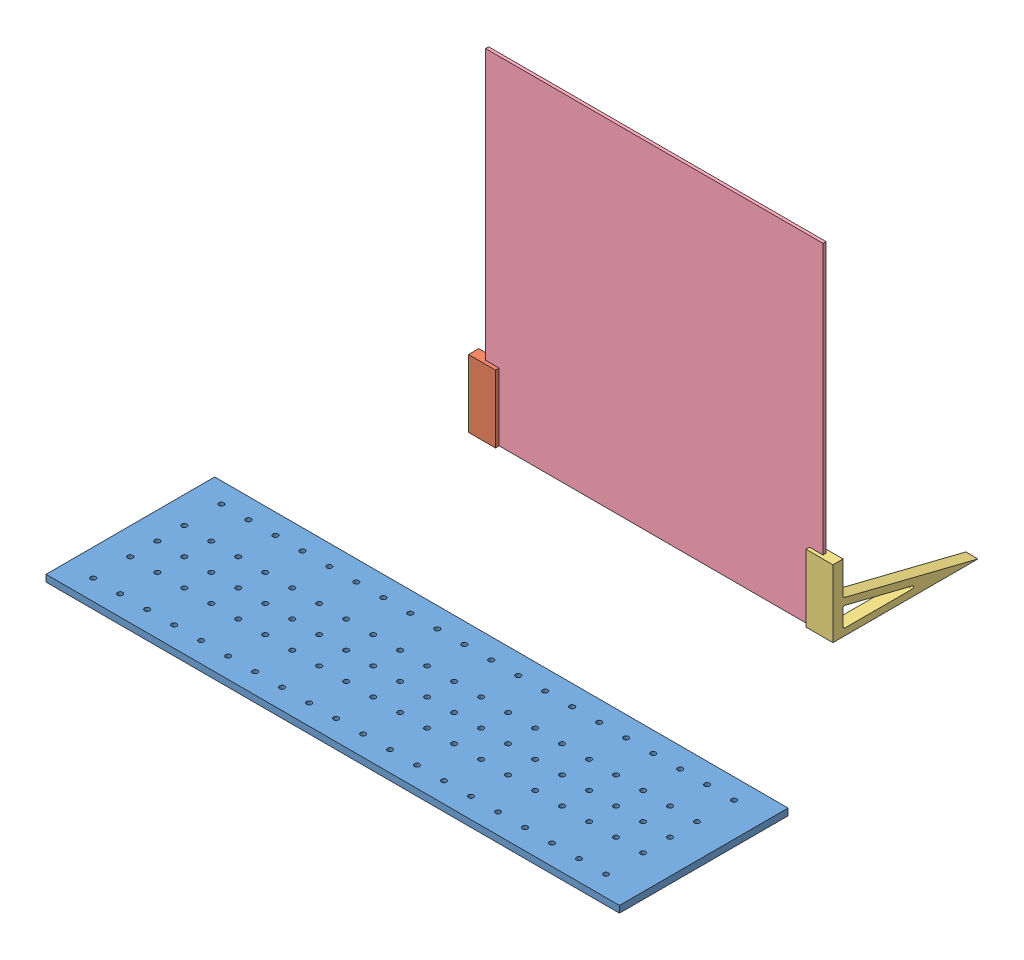
SolidWorks assembly Perspex Rig Assembly, configuration Default. Lengths in mm.
Overall size (850 500 730.2).
4 component instances, 4 part files, 7 mates.
Components (placement in the parent):
- Robot Base Plate 850x250-1: Robot Base Plate 850x250 [Default] at (362.6936 417.3937 642.876) size (850 10 250)
- Perspex Stand Left Side-1: Perspex Stand Left Side [Default] at (68.8998 407.6445 247.626) size (40 100 215.2)
- Perspex Stand Right Side-1: Perspex Stand Right Side [Default] at (568.8998 507.6445 247.426) x (-1 0 0) z (0 0 1) size (40 100 215)
- Perspex 500x500-1: Perspex 500x500 [Default] at (318.8998 657.6445 242.926) x (1 0 0) z (0 -1 0) size (500 4.5 500)
Mates (geometry in assembly coordinates):
- Coincident4: coincident anti-aligned: plane of Perspex Stand Left Side-1 through (68.8998 507.6445 247.626) normal (1 0 0); plane of Perspex 500x500-1 through (68.8998 907.6445 247.426) normal (-1 0 0)
- Coincident5: coincident anti-aligned: plane of Perspex Stand Right Side-1 through (568.8998 407.6445 247.426) normal (-1 0 0); plane of Perspex 500x500-1 through (568.8998 907.6445 247.426) normal (1 0 0)
- Coincident6: coincident aligned: plane of Perspex Stand Right Side-1 through (568.8998 407.6445 247.426) normal (0 -1 0); plane of Perspex 500x500-1 through (68.8998 407.6445 247.426) normal (0 -1 0)
- Coincident7: coincident aligned: plane of Perspex Stand Left Side-1 through (68.8998 407.6445 247.626) normal (0 -1 0); plane of Perspex 500x500-1 through (68.8998 407.6445 247.426) normal (0 -1 0)
- Coincident9: coincident anti-aligned: plane of Perspex Stand Right Side-1 through (568.8998 407.6445 242.926) normal (0 0 1); plane of Perspex 500x500-1 through (318.8998 657.6445 242.926) normal (0 0 -1)
- Coincident10: coincident anti-aligned: plane of Perspex Stand Left Side-1 through (68.8998 507.6445 242.926) normal (0 0 1); plane of Perspex 500x500-1 through (318.8998 657.6445 242.926) normal (0 0 -1)
- Distance3: distance = 265 mm anti-aligned: plane of Perspex Stand Left Side-1 through (88.8998 507.6445 252.876) normal (0 0 1); plane of Robot Base Plate 850x250-1 through (-62.3064 427.3937 517.876) normal (0 0 -1)
